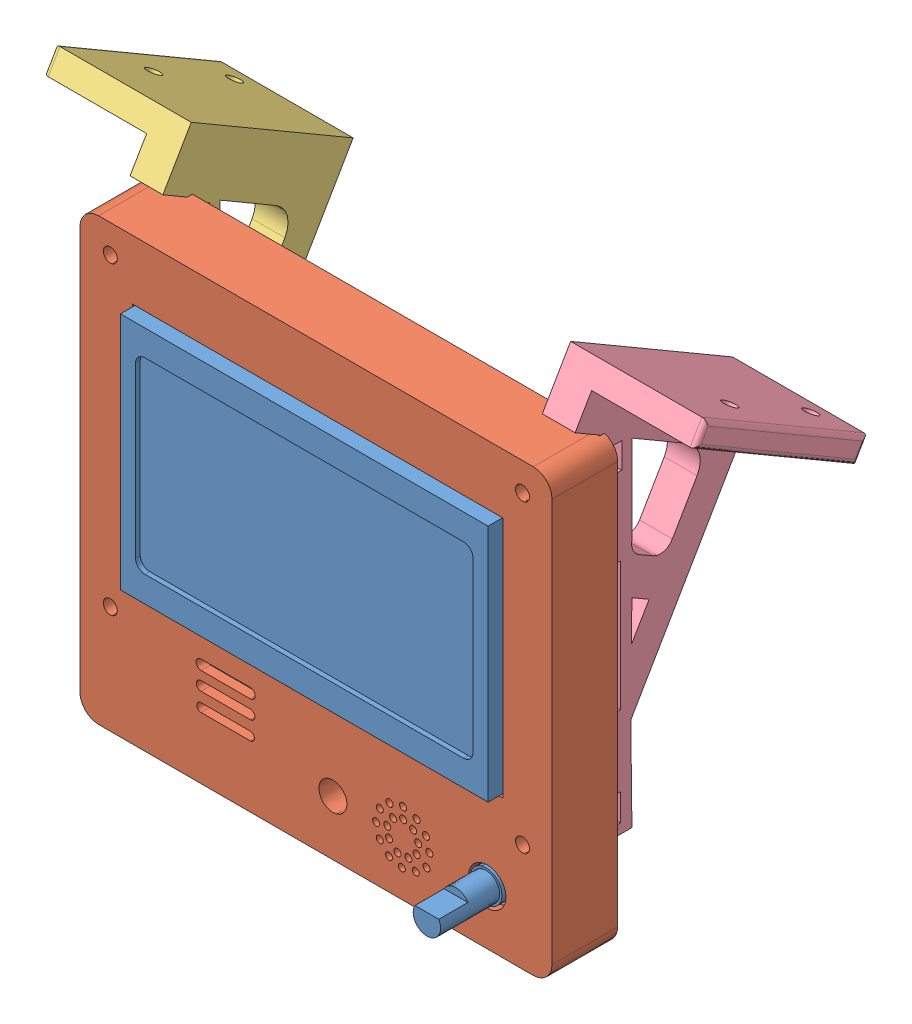
SolidWorks assembly Screen Assembly, configuration Default. Lengths in mm.
Overall size (138.95 107.39 82.56).
4 component instances, 4 part files, 6 mates.
Components (placement in the parent):
- Full Graphic Smart Controller-2: Full Graphic Smart Controller [Default] at (-62.6096 73.8061 19.9222) size (102.9 86.75 34.7)
- LCD_Case-2: LCD_Case [Default] at (-68.3227 84.8365 18.8222) size (100.75 94 14)
- LCD_Holder_Left-1: LCD_Holder_Left [Default] at (-103.0846 92.3537 17.2607) x (1 0 0) z (0 -0.863792 0.503849) size (29 50.29 77.65)
- LCD_Holder_Right-1: LCD_Holder_Right [Default] at (-15.1346 92.3537 17.2607) x (1 0 0) z (0 -0.863792 0.503849) size (29 50.29 77.65)
Mates (geometry in assembly coordinates):
- Coincident20: coincident anti-aligned: plane of Full Graphic Smart Controller-2 through (-62.6096 73.8061 30.8222) normal (0 0 1); plane of LCD_Case-2 through (-68.3227 84.8365 30.8222) normal (0 0 -1)
- Concentric2: concentric aligned: circle of Full Graphic Smart Controller-2; circle of LCD_Case-2
- Concentric3: concentric aligned: circle of Full Graphic Smart Controller-2; circle of LCD_Holder_Left-1
- Coincident24: coincident anti-aligned: plane of Full Graphic Smart Controller-2 through (-108.9846 117.1811 19.9222) normal (0 0 -1); plane of LCD_Holder_Left-1 through (-110.0846 95.2811 19.9222) normal (0 0 1)
- Coincident25: coincident anti-aligned: plane of Full Graphic Smart Controller-2 through (-108.9846 117.1811 19.9222) normal (0 0 -1); plane of LCD_Holder_Right-1 through (-22.1346 95.2811 19.9222) normal (0 0 1)
- Concentric5: concentric aligned: circle of Full Graphic Smart Controller-2; circle of LCD_Holder_Right-1
